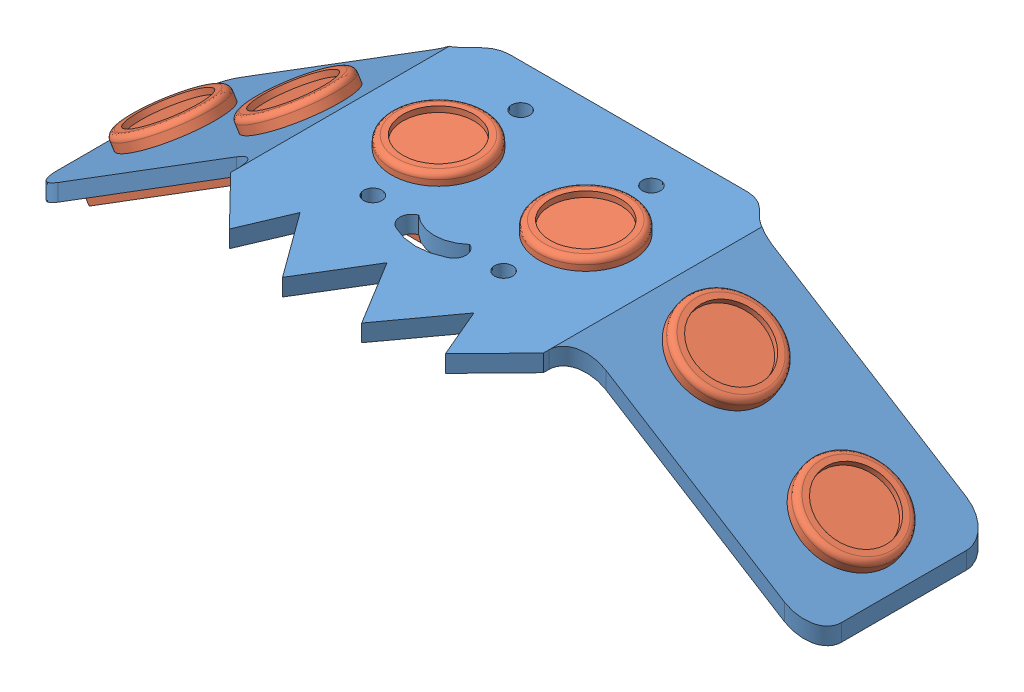
SolidWorks assembly 超声波装配体, configuration 默认. Lengths in mm.
Overall size (137.8 31.58 53.91).
4 component instances, 2 part files, 9 mates.
Components (placement in the parent):
- 超声波模块支架1-1: 超声波模块支架1 [默认] at (-1.0229 -107.3386 96.3475) size (137.8 28.86 53.91)
- 超声波模块-1: 超声波模块 [默认] at (-1.0729 26.7705 131.3475) x (1 0 0) z (0 1 0) size (45 20 8)
- 超声波模块-2: 超声波模块 [默认] at (44.1981 15.1636 131.3475) x (0.848126 -0.529795 0) z (0.529795 0.848126 0) size (45 20 8)
- 超声波模块-3: 超声波模块 [默认] at (-46.3288 15.1106 131.3475) x (0.848126 0.529795 0) z (-0.529795 0.848126 0) size (45 20 8)
Mates (geometry in assembly coordinates):
- 同心1: concentric: cylinder of assembly; cylinder of assembly; cylinder of 超声波模块支架1-1 through (-13.9729 32.7705 131.3475) axis (0 -1 0) radius 8.25; cylinder of 超声波模块-1 through (-13.9729 34.7705 131.3475) axis (0 -1 0) radius 8.25
- 同心2: concentric: cylinder of assembly; cylinder of assembly; cylinder of 超声波模块支架1-1 through (11.9271 32.7705 131.3475) axis (0 -1 0) radius 8.25; cylinder of 超声波模块-1 through (11.9271 34.7705 131.3475) axis (0 -1 0) radius 8.25
- 重合1: coincident: plane of assembly; plane of assembly; plane of 超声波模块支架1-1 through (-1.0229 29.7705 96.3475) normal (0 -1 0); plane of 超声波模块-1 through (-1.0729 29.7705 131.3475) normal (0 1 0)
- 重合2: coincident: plane of assembly; plane of assembly; plane of 超声波模块支架1-1 through (68.3035 3.643 197.8166) normal (-0.529795 -0.848126 0); plane of 超声波模块-2 through (45.7875 17.708 131.3475) normal (0.529795 0.848126 0)
- 同心3: concentric: cylinder of assembly; cylinder of assembly; cylinder of 超声波模块支架1-1 through (56.5718 10.4342 131.3475) axis (0.529795 0.848126 0) radius 8.25; cylinder of 超声波模块-2 through (59.4621 15.0612 131.3475) axis (-0.529795 -0.848126 0) radius 8.25
- 同心5: concentric: cylinder of assembly; cylinder of assembly; cylinder of 超声波模块支架1-1 through (34.6053 24.1559 131.3475) axis (0.529795 0.848126 0) radius 8.25; cylinder of 超声波模块-2 through (37.4957 28.7829 131.3475) axis (-0.529795 -0.848126 0) radius 8.25
- 重合3: coincident: plane of assembly; plane of assembly; plane of 超声波模块支架1-1 through (-70.3494 3.643 197.8166) normal (0.529795 -0.848126 0); plane of 超声波模块-3 through (-47.9182 17.655 131.3475) normal (-0.529795 0.848126 0)
- 同心6: concentric: cylinder of assembly; cylinder of assembly; cylinder of 超声波模块支架1-1 through (-36.6512 24.1559 131.3475) axis (-0.529795 0.848126 0) radius 8.25; cylinder of 超声波模块-3 through (-39.5415 28.7829 131.3475) axis (0.529795 -0.848126 0) radius 8.25
- 同心7: concentric: cylinder of assembly; cylinder of assembly; cylinder of 超声波模块支架1-1 through (-58.6176 10.4342 131.3475) axis (-0.529795 0.848126 0) radius 8.25; cylinder of 超声波模块-3 through (-61.508 15.0612 131.3475) axis (0.529795 -0.848126 0) radius 8.25
